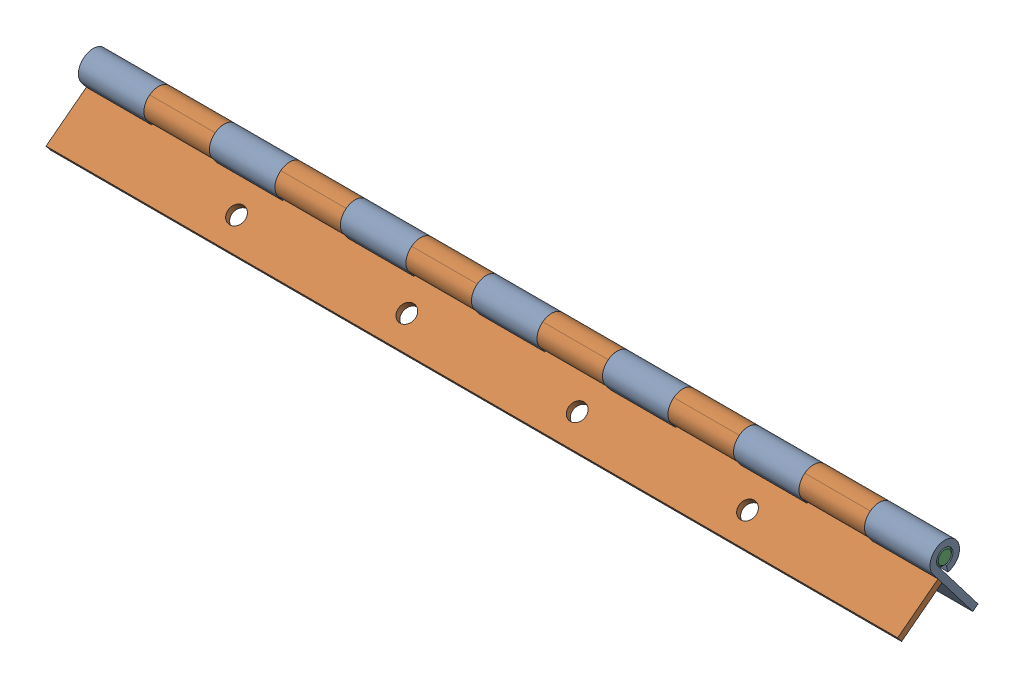
SolidWorks assembly CR25-101-17, configuration Default. Lengths in mm.
Overall size (165.1 15.84 21.81).
3 component instances, 3 part files, 3 mates.
Components (placement in the parent):
- CR25-101-17A-1: CR25-101-17A [Default] x (1 0 0) z (0 0.606542 -0.795051) size (165.1 15.56 5.71)
- CR25-101-17B-1: CR25-101-17B [Default] x (1 0 0) z (0 0.795051 0.606542) size (165.1 15.56 5.71)
- CR25-101-17C-1: CR25-101-17C [Default] at origin size (165.1 3.17 3.17)
Mates (geometry in assembly coordinates):
- Hinge1: hinge aligned: cylinder of CR25-101-17A-1 through (-152.4 0 0) axis (1 0 0) radius 2.8575; cylinder of CR25-101-17B-1 through (152.4 0 0) axis (-1 0 0) radius 2.8575; plane of CR25-101-17A-1 through (152.4 0 0) normal (1 0 0); plane of CR25-101-17B-1 through (152.4 0 0) normal (1 0 0)
- Concentric1: concentric aligned: cylinder of CR25-101-17A-1 through (-152.4 0 0) axis (1 0 0) radius 1.5875; cylinder of CR25-101-17C-1 through (-152.4 0 0) axis (1 0 0) radius 1.5875
- Width1: width aligned: plane of CR25-101-17A-1 through (152.4 0 0) normal (1 0 0); plane of CR25-101-17A-1 through (-12.7 -4.0051 0.5387) normal (-1 0 0); plane of CR25-101-17C-1 through (152.4 0 0) normal (1 0 0); plane of CR25-101-17C-1 through (-12.7 -1.5875 -1.5875) normal (-1 0 0)
